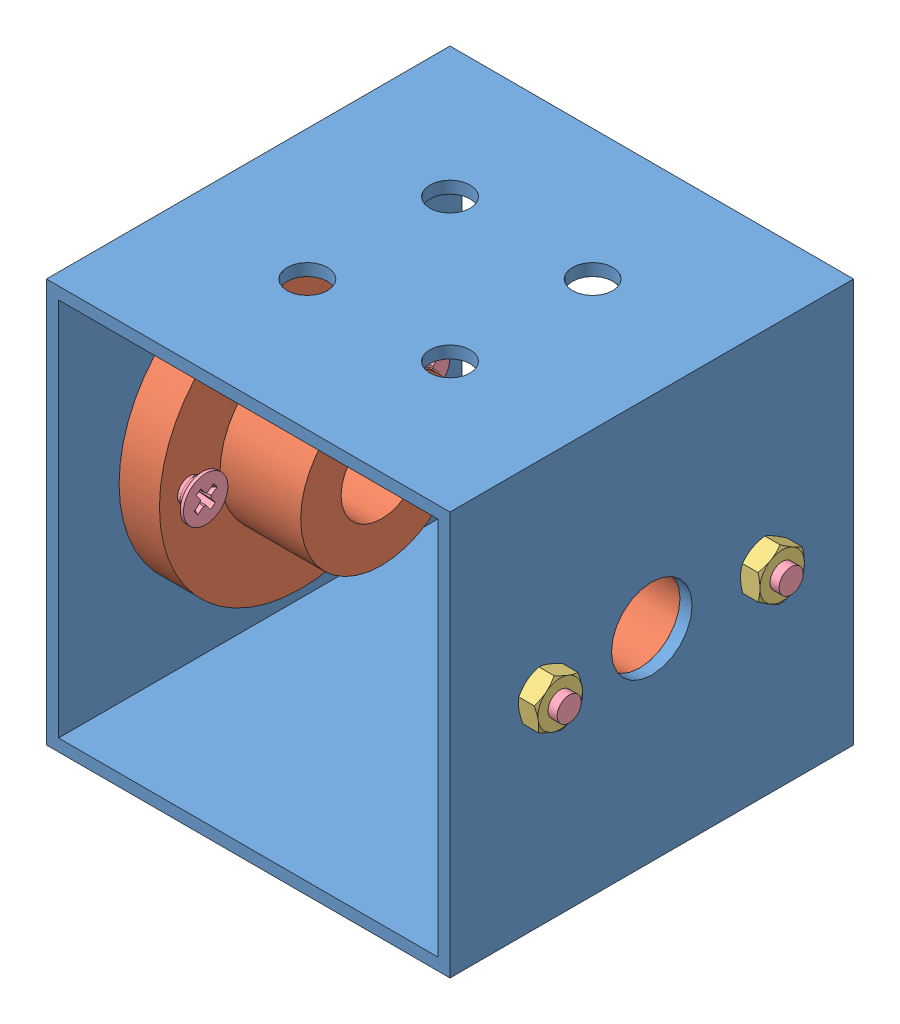
SolidWorks assembly Caixa Alumínio, configuration Valor predeterminado. Lengths in mm.
Overall size (57.04 50 50).
11 component instances, 4 part files, 18 mates.
Components (placement in the parent):
- Caixa Aluminio 1-1: Caixa Aluminio 1 [Valor predeterminado] at (-10.4524 1.2722 25) size (50 50 50)
- Bucha 10 mm-1: Bucha 10 mm [Valor predeterminado] at (-33.9524 1.2722 50) x (0 -1 0) z (0 0 1) size (35 15 35)
- Bucha 10 mm-2: Bucha 10 mm [Valor predeterminado] at (13.0476 1.2722 50) x (0 1 0) z (0 0 1) size (35 15 35)
- hex nut style 1 gradeab_iso-1: hex nut style 1 gradeab_iso [ISO - 4032 - M3 - D - N] at (14.5476 1.2722 36.25) x (0 -0.866025 0.5) z (-1 0 0) size (5.5 6.35 2.4)
- countersunk flat head cross recess screw_iso-1: countersunk flat head cross recess screw_iso [ISO 7046-1 - M3 x 12 - Z - 12N] at (6.0663 1.2722 36.25) x (1 0 0) z (0 -0.400835 0.91615) size (12 5.5 5.5)
- hex nut style 1 gradeab_iso-2: hex nut style 1 gradeab_iso [ISO - 4032 - M3 - D - N] at (-35.4524 1.2722 36.25) x (0 0.249017 -0.968499) z (1 0 0) size (5.5 6.35 2.4)
- countersunk flat head cross recess screw_iso-2: countersunk flat head cross recess screw_iso [ISO 7046-1 - M3 x 12 - Z - 12N] at (-26.971 1.2722 36.25) x (-1 0 0) z (0 -0.725577 0.688141) size (12 5.5 5.5)
- hex nut style 1 gradeab_iso-3: hex nut style 1 gradeab_iso [ISO - 4032 - M3 - D - N] at (14.5476 1.2722 63.75) x (0 -0.934192 0.356771) z (-1 0 0) size (5.5 6.35 2.4)
- countersunk flat head cross recess screw_iso-3: countersunk flat head cross recess screw_iso [ISO 7046-1 - M3 x 12 - Z - 12N] at (6.0663 1.2722 63.75) x (1 0 0) z (0 -0.540657 0.841243) size (12 5.5 5.5)
- countersunk flat head cross recess screw_iso-4: countersunk flat head cross recess screw_iso [ISO 7046-1 - M3 x 12 - Z - 12N] at (-26.971 1.2722 63.75) x (-1 0 0) z (0 -0.594897 0.803802) size (12 5.5 5.5)
- hex nut style 1 gradeab_iso-4: hex nut style 1 gradeab_iso [ISO - 4032 - M3 - D - N] at (-35.4524 1.2722 63.75) x (0 0.146862 -0.989157) z (1 0 0) size (5.5 6.35 2.4)
Mates (geometry in assembly coordinates):
- Coincident1: coincident: plane of Caixa Aluminio 1-1 through (-33.9524 -22.2278 75) normal (1 0 0); plane of Bucha 10 mm-1 through (-33.9524 1.2722 50) normal (-1 0 0)
- Concentric1: concentric: circle of Caixa Aluminio 1-1; circle of Bucha 10 mm-1
- Concentric2: concentric: circle of Caixa Aluminio 1-1; circle of Bucha 10 mm-1
- Coincident4: coincident: plane of Caixa Aluminio 1-1 through (13.0476 -22.2278 75) normal (-1 0 0); plane of Bucha 10 mm-2 through (13.0476 1.2722 50) normal (1 0 0)
- Concentric3: concentric: circle of Caixa Aluminio 1-1; circle of Bucha 10 mm-2
- Concentric4: concentric: circle of Caixa Aluminio 1-1; circle of Bucha 10 mm-2
- Concentric5: concentric: circle of hex nut style 1 gradeab_iso-1; cylinder of countersunk flat head cross recess screw_iso-1 through (-0.2837 1.2722 36.25) axis (-1 0 0) radius 1.5
- Concentric6: concentric: circle of hex nut style 1 gradeab_iso-3; cylinder of countersunk flat head cross recess screw_iso-3 through (-0.2837 1.2722 63.75) axis (-1 0 0) radius 1.5
- Concentric7: concentric: circle of hex nut style 1 gradeab_iso-2; cylinder of countersunk flat head cross recess screw_iso-2 through (-20.621 1.2722 36.25) axis (1 0 0) radius 1.5
- Concentric8: concentric: cylinder of countersunk flat head cross recess screw_iso-4 through (-20.621 1.2722 63.75) axis (1 0 0) radius 1.5; circle of hex nut style 1 gradeab_iso-4
- Coincident7: coincident: circle of Bucha 10 mm-1; circle of countersunk flat head cross recess screw_iso-2
- Coincident8: coincident: circle of Bucha 10 mm-1; circle of countersunk flat head cross recess screw_iso-4
- Coincident9: coincident: circle of Bucha 10 mm-2; circle of countersunk flat head cross recess screw_iso-3
- Coincident10: coincident: circle of countersunk flat head cross recess screw_iso-1; circle of Bucha 10 mm-2
- Coincident11: coincident: plane of Caixa Aluminio 1-1 through (-35.4524 -23.7278 75) normal (-1 0 0); plane of hex nut style 1 gradeab_iso-2 through (-35.4524 4.3476 37.0407) normal (1 0 0)
- Coincident12: coincident: plane of Caixa Aluminio 1-1 through (14.5476 -23.7278 75) normal (1 0 0); plane of hex nut style 1 gradeab_iso-1 through (14.5476 2.8599 39) normal (-1 0 0)
- Coincident13: coincident: plane of Caixa Aluminio 1-1 through (14.5476 -23.7278 75) normal (1 0 0); plane of hex nut style 1 gradeab_iso-3 through (14.5476 2.4051 66.7165) normal (-1 0 0)
- Coincident14: coincident: plane of Caixa Aluminio 1-1 through (-35.4524 -23.7278 75) normal (-1 0 0); plane of hex nut style 1 gradeab_iso-4 through (-35.4524 4.4132 64.2163) normal (1 0 0)
